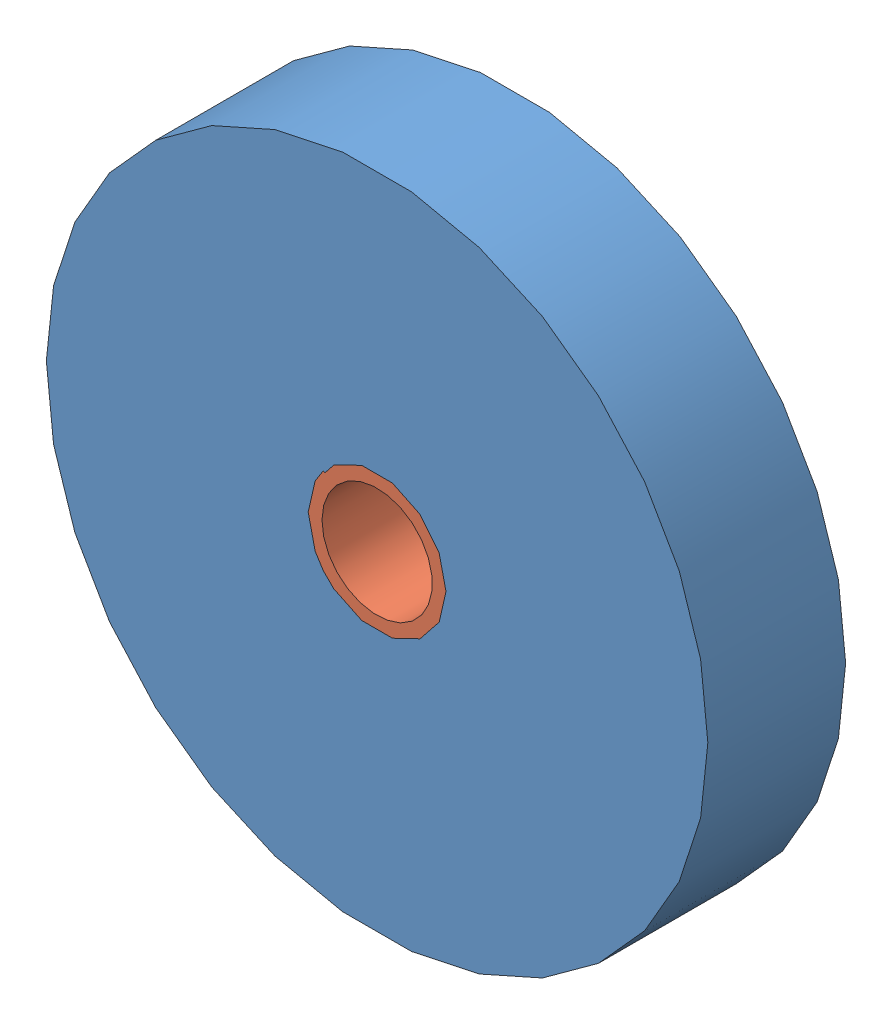
SolidWorks assembly Belt Sander Disk and Bushing 5-2, configuration Default. Lengths in mm.
Overall size (76.2 76.2 15.88).
2 component instances, 2 part files, 2 mates.
Components (placement in the parent):
- Belt Sander Disk 5-2-1: Belt Sander Disk 5-2 [Default] at origin size (76.2 76.2 15.88)
- Belt Sander Bushing 5-2-1: Belt Sander Bushing 5-2 [Default] at origin size (15.91 15.91 15.88)
Mates (geometry in assembly coordinates):
- Coincident1: coincident aligned: plane of Belt Sander Disk 5-2-1 through (0 0 0) normal (0 0 -1); plane of Belt Sander Bushing 5-2-1 through (0 0 0) normal (0 0 -1)
- Concentric1: concentric aligned: cylinder of Belt Sander Disk 5-2-1 through (0 0 15.875) axis (0 0 -1) radius 7.9375; cylinder of Belt Sander Bushing 5-2-1 through (0 0 15.875) axis (0 0 -1) radius 7.954
